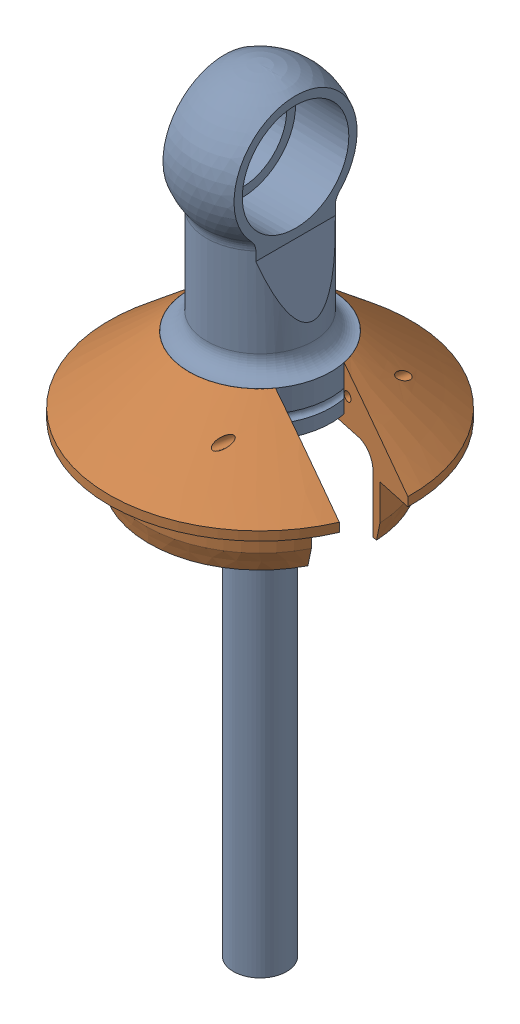
SolidWorks assembly Assem4, configuration Default. Lengths in mm.
Overall size (63.67 138.11 64.05).
2 component instances, 2 part files, 2 mates.
Components (placement in the parent):
- Penske7800_Shaft-1: Penske7800_Shaft [Default] at (-14.3604 47.7832 13.4022) size (25.4 138.11 25.4)
- Penske7800_Tophat-1: Penske7800_Tophat [Default] at (-14.3604 9.6832 13.4022) x (0.977467 0 0.21109) z (-0.21109 0 0.977467) size (53.48 23.02 53.98)
Mates (geometry in assembly coordinates):
- Concentric1: concentric aligned: cylinder of Penske7800_Shaft-1 through (-14.3604 -77.6293 13.4022) axis (0 1 0) radius 4.7625; cylinder of Penske7800_Tophat-1 through (-14.3604 52.1647 13.4022) axis (0 1 0) radius 19.05
- Coincident1: coincident anti-aligned: plane of Penske7800_Shaft-1 through (-27.0604 11.2707 13.4022) normal (0 -1 0); plane of Penske7800_Tophat-1 through (-11.6796 11.2707 0.9884) normal (0 1 0)
